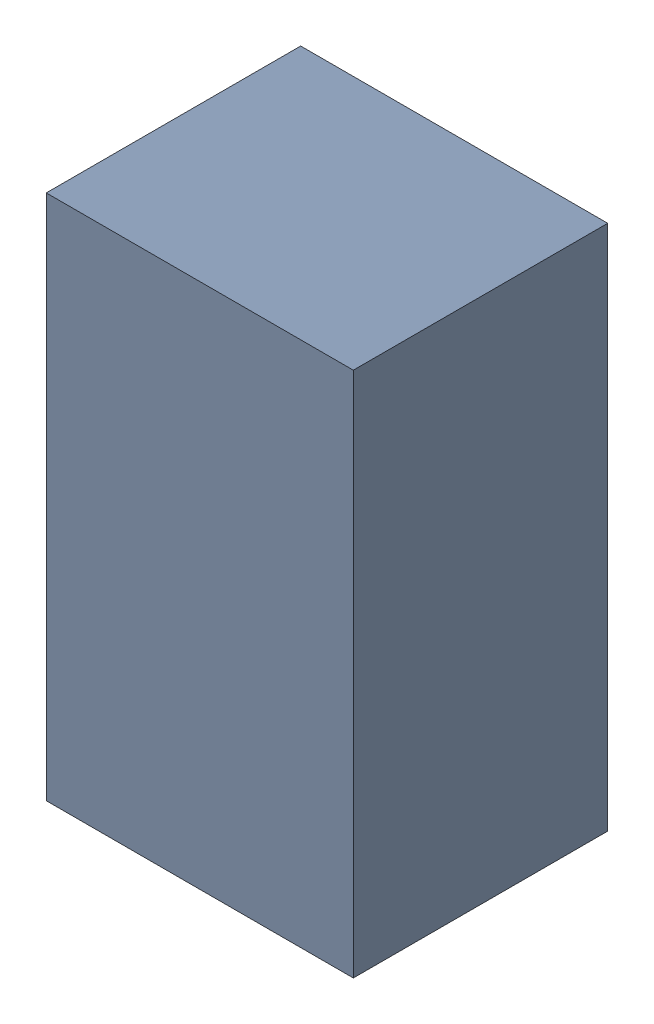
SolidWorks assembly U1, configuration Default. Lengths in mm.
Overall size (1.75 3 1.45).
2 component instances, 1 part files, 0 mates.
Components (placement in the parent):
- 959209616-1: 959209616 [Default] at (137.668 84.449 0) size (1.75 3 1.45)
  - Extruded-27-1: Extruded-27 [Default] at origin size (1.75 3 1.45)
